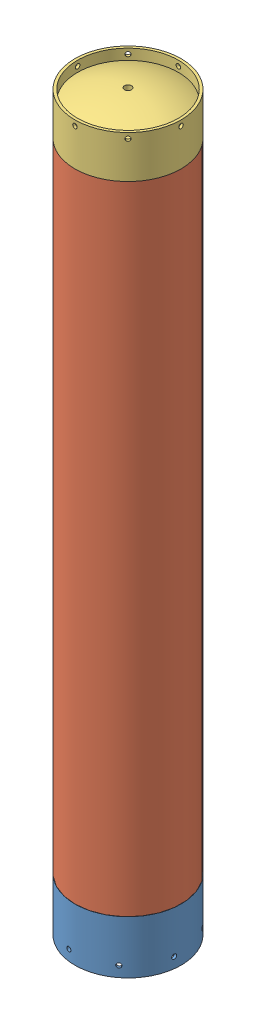
SolidWorks assembly Assem1, configuration Default. Lengths in mm.
Overall size (156.32 877.88 156.32).
3 component instances, 3 part files, 6 mates.
Components (placement in the parent):
- End Cap sim-1: End Cap sim [Default] at (0 63.5 0) x (-0.963635 0 0.267223) z (0.267223 0 0.963635) size (127 63.5 127)
- Cylindrical Part sim-1: Cylindrical Part sim [Default] at (0 63.5 0) size (127 762 127)
- Top Cap Simulation-1: Top Cap Simulation [Default] at (0 825.5 0) size (127 52.38 127)
Mates (geometry in assembly coordinates):
- Coincident1: coincident anti-aligned: plane of End Cap sim-1 through (0 0 0) normal (0 -1 0); plane of assembly through (0 0 0) normal (0 1 0)
- Concentric1: concentric anti-aligned: cone of End Cap sim-1 through (0 63.5 0) axis (0 -1 0); line of assembly
- Coincident2: coincident anti-aligned: plane of End Cap sim-1 through (0 63.5 0) normal (0 1 0); plane of Cylindrical Part sim-1 through (-60.325 63.5 0) normal (0 -1 0)
- Concentric2: concentric anti-aligned: cylinder of End Cap sim-1 through (0 -63.561 0) axis (0 -1 0) radius 63.5; cylinder of Cylindrical Part sim-1 through (0 882.687 0) axis (0 1 0) radius 63.5
- Coincident3: coincident anti-aligned: plane of Cylindrical Part sim-1 through (-60.325 825.5 0) normal (0 1 0); plane of Top Cap Simulation-1 through (0 825.5 0) normal (0 -1 0)
- Concentric3: concentric aligned: cylinder of Cylindrical Part sim-1 through (0 882.687 0) axis (0 1 0) radius 63.5; cylinder of Top Cap Simulation-1 through (0 952.561 0) axis (0 1 0) radius 63.5
